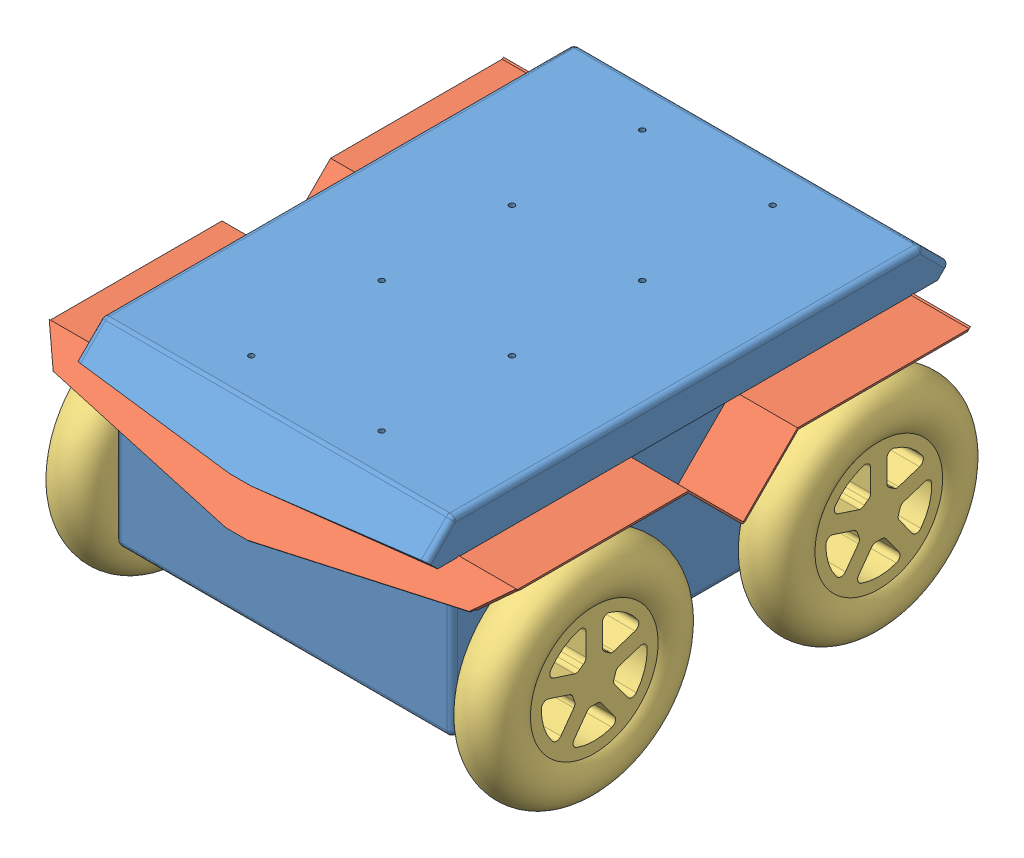
SolidWorks assembly jackel_platform, configuration Default. Lengths in mm.
Overall size (430 249.5 503.1).
6 component instances, 3 part files, 7 mates.
Components (placement in the parent):
- Simplified Model Base-1: Simplified Model Base [Default] at (6.1952 31.8117 12.8284) size (337.59 184 494.34)
- Simplified Model Fenders-1: Simplified Model Fenders [Default] at (6.1952 33.2242 14.8284) size (430 52.25 503.1)
- Simplified Wheel-1: Simplified Wheel [Default] at (193.9889 131.8117 143.8284) x (0 0 -1) z (1 0 0) size (200 200 50)
- Simplified Wheel-2: Simplified Wheel [Default] at (193.9889 131.8117 -118.1716) x (0 0 -1) z (1 0 0) size (200 200 50)
- Simplified Wheel-3: Simplified Wheel [Default] at (-181.5986 131.8117 -118.1716) x (0 0 -1) z (1 0 0) size (200 200 50)
- Simplified Wheel-4: Simplified Wheel [Default] at (-181.5986 131.8117 143.8284) x (0 0 -1) z (1 0 0) size (200 200 50)
Mates (geometry in assembly coordinates):
- ProfileCenter2: profile center aligned: circle of Simplified Wheel-1; circle of Simplified Model Base-1
- ProfileCenter3: profile center aligned: circle of Simplified Wheel-2; circle of Simplified Model Base-1
- ProfileCenter4: profile center aligned: circle of Simplified Wheel-3; circle of Simplified Model Base-1
- ProfileCenter5: profile center aligned: circle of Simplified Wheel-4; circle of Simplified Model Base-1
- Width2: width anti-aligned: plane of Simplified Model Base-1 through (-148.8048 247.3117 217.8284) normal (-1 0 0); plane of Simplified Model Base-1 through (161.1952 102.3117 217.8284) normal (1 0 0); plane of Simplified Model Fenders-1 through (-148.8048 247.3117 -210.8493) normal (1 0 0); plane of Simplified Model Fenders-1 through (161.1952 196.1892 -210.8493) normal (-1 0 0)
- Coincident3: coincident anti-aligned: plane of Simplified Model Base-1 through (-155.5908 247.3117 -225.8579) normal (0 -1 0); plane of Simplified Model Fenders-1 through (221.1952 247.3117 -35.1716) normal (0 1 0)
- Coincident6: coincident: plane of Simplified Model Base-1 through (156.1952 102.3117 222.8284) normal (0 0 1); line of Simplified Model Fenders-1 through (-148.8048 247.3117 222.8284) axis (1 0 0)
